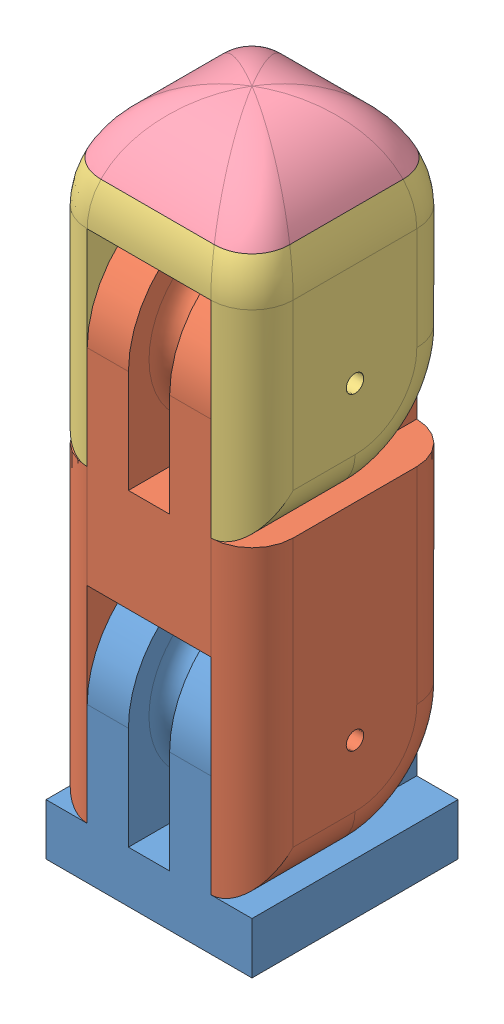
SolidWorks assembly Thumb and Lid Assembly, configuration Default. Lengths in mm.
Overall size (20 65 20).
5 component instances, 4 part files, 3 mates.
Components (placement in the parent):
- Thumb Joint-1: Thumb Joint [Default] at (-0.2704 3.0981 27.2461) size (20 25 20)
- Finger Assembly 1-1: Finger Assembly 1 [Default] at (1.6517 -23.7789 -26.1863) size (20 60 20)
  - Finger Body 1-2: Finger Body 1 [Default] at (8.0779 51.877 43.4324) size (20 50 20)
  - Finger Top-1: Finger Top [Default] at (8.0779 81.877 43.4324) size (20 24 20)
  - Finger Tip-1: Finger Tip [Default] at (8.0779 81.877 43.4324) size (18.77 6 18.77)
Mates (geometry in assembly coordinates):
- Coincident1: coincident anti-aligned: plane of Thumb Joint-1 through (15.7296 18.0981 7.2461) normal (1 0 0); plane of Finger Assembly 1-1/Finger Body 1-2 through (15.7296 18.0981 7.2461) normal (-1 0 0)
- Concentric1: concentric aligned: circle of Thumb Joint-1; circle of Finger Assembly 1-1/Finger Body 1-2
- LimitAngle1: limit planar angle = 1.570796 rad aligned: plane of Finger Assembly 1-1/Finger Body 1-2 through (-0.2704 38.0981 7.2461) normal (0 0 -1); plane of Thumb Joint-1 through (-0.2704 8.0981 27.2461) normal (0 1 0)
